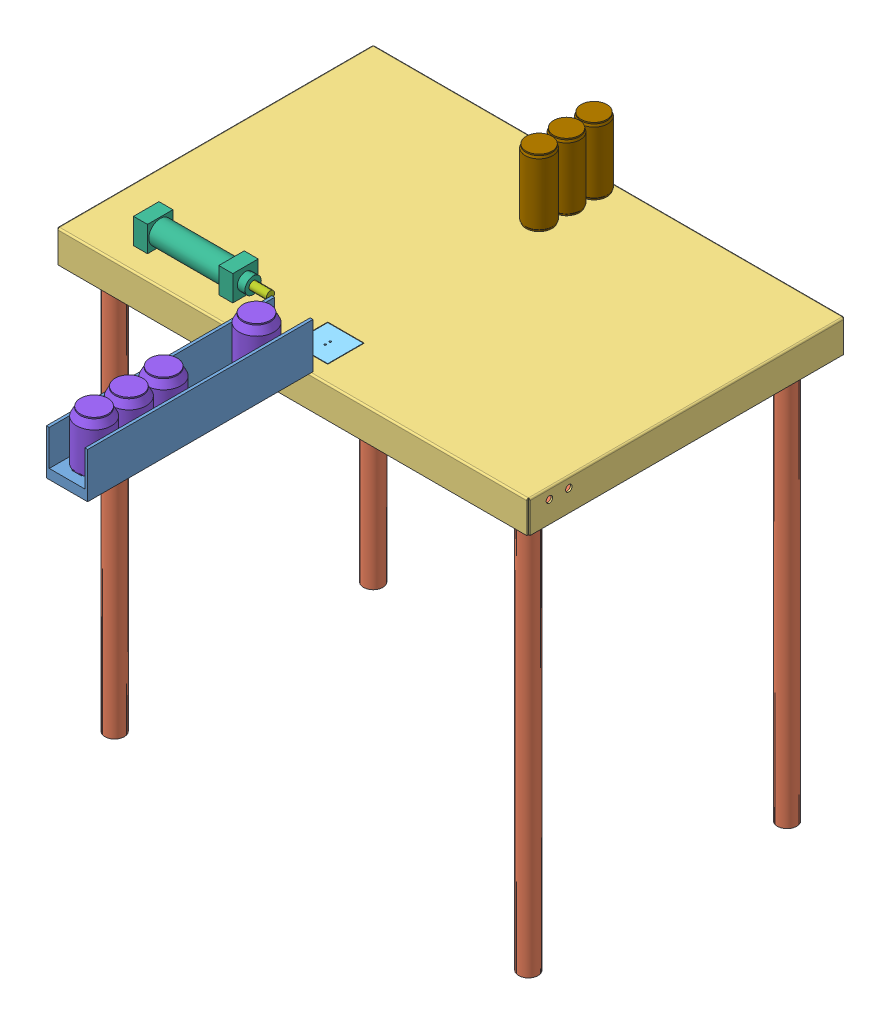
SolidWorks assembly Full_Assembly_v8, configuration Default. Lengths in mm.
Overall size (927.1 1032.54 1072.2).
19 component instances, 12 part files, 63 mates.
Components (placement in the parent):
- Goose Output-1: Goose Output [Default] at (293.9688 417.0931 1038.3317) size (80.96 88.9 442.73)
- M37 Metal Table-1: M37 Metal Table [Default] at (-122.75 348.1681 1031.9817) size (914.4 863.6 609.6)
- Table Topper-1: Table Topper [Default] at (-125.925 348.1681 1035.1567) size (927.1 62.58 622.3)
- Load Cell Assembly-1: Load Cell Assembly [Default] at (309.0555 355.827 890.1864) size (69.85 23.2 103.99)
  - Load Cell and Brace-1: Load Cell and Brace [Default] at (-9.1055 31.7162 92.7424) size (69 14.2 83)
  - scalePlate_v2_234-1: scalePlate_v2_234 [Default] at (-9.5305 54.9162 113.7283) x (0 0 -1) z (-1 0 0) size (69.85 9 69.85)
- Cylinder-1: Cylinder [Default] at (-22.0508 460.7431 943.9897) x (0 0 1) z (1 0 0) size (50 50 210)
- Rod-1: Rod [Default] at (221.9492 435.7431 968.9897) x (0 0.637822 -0.770184) z (0 0.770184 0.637822) size (16 134 16)
- can355mL-1: can355mL [Default] at (334.45 410.7431 1291.3582) x (0 0 -1) z (1 0 0) size (68.26 122.24 68.26)
- can355mL-2: can355mL [Default] at (334.45 410.7431 1427.8832) x (0 0 -1) z (1 0 0) size (68.26 122.24 68.26)
- can355mL-3: can355mL [Default] at (334.45 410.7431 1359.6207) x (0 0 -1) z (1 0 0) size (68.26 122.24 68.26)
- can250mL-1: can250mL [Default] at (334.45 410.7431 553.8493) x (-0.934308 0 -0.356465) z (0.356465 0 -0.934308) size (53.98 131.76 53.98)
- can250mL-2: can250mL [Default] at (334.45 410.7431 499.8743) x (0.439436 0 -0.898274) z (0.898274 0 0.439436) size (53.98 131.76 53.98)
- can250mL-3: can250mL [Default] at (334.45 410.7431 445.8993) x (0.515444 0 0.856923) z (-0.856923 0 0.515444) size (53.98 131.76 53.98)
- can355mL-7: can355mL [Default] at (334.45 410.7431 1108.8451) x (0 0 -1) z (1 0 0) size (68.26 122.24 68.26)
- AmpCase_Assembly_v1-1: AmpCase_Assembly_v1 [Default] at (378.0256 448.8639 898.6464) x (0 0 -1) z (-1 0 0) size (83 33 59)
  - AmpCase_LID_83x59x33_v1-1: AmpCase_LID_83x59x33_v1 [Default] at (42.2994 74.2958 -6.3457) x (1 0 0) z (0 0 -1) size (83 7 59)
  - AmpCase83x59x33_v1-1: AmpCase83x59x33_v1 [Default] at (42.2994 41.2958 52.6543) size (83 26 59)
- Solenoid_v1-1: Solenoid_v1 [Default] at (452.5858 385.5681 857.7853) size (118 22 83)
Mates (geometry in assembly coordinates):
- Width1: width aligned: plane of M37 Metal Table-1 through (791.65 373.5681 1031.9817) normal (1 0 0); plane of M37 Metal Table-1 through (-122.75 373.5681 1031.9817) normal (-1 0 0); plane of Table Topper-1 through (798 407.5681 1035.1567) normal (1 0 0); plane of Table Topper-1 through (-129.1 407.5681 1035.1567) normal (-1 0 0)
- Width2: width aligned: plane of M37 Metal Table-1 through (-122.75 373.5681 1031.9817) normal (0 0 1); plane of M37 Metal Table-1 through (-122.75 373.5681 422.3817) normal (0 0 -1); plane of Table Topper-1 through (-125.925 407.5681 1038.3317) normal (0 0 1); plane of Table Topper-1 through (-125.925 407.5681 416.0317) normal (0 0 -1)
- Distance1: distance = 863.6 mm aligned: plane of M37 Metal Table-1 through (-122.75 -446.5069 1031.9817) normal (0 -1 0); plane of Goose Output-1 through (374.9313 417.0931 1481.0664) normal (0 -1 0)
- LimitDistance1: limit distance = 423.0687 mm aligned: plane of Goose Output-1 through (374.9313 505.9931 1481.0664) normal (1 0 0); plane of Table Topper-1 through (798 407.5681 1035.1567) normal (1 0 0)
- LimitDistance2: limit distance = 423.0687 mm aligned: plane of Table Topper-1 through (-129.1 407.5681 1035.1567) normal (-1 0 0); plane of Goose Output-1 through (293.9688 417.0931 1481.0664) normal (-1 0 0)
- Parallel1: parallel aligned: plane of Goose Output-1 through (299.525 436.1431 1481.0664) normal (0 1 0); plane of Table Topper-1 through (-125.925 410.7431 1035.1567) normal (0 1 0)
- Coincident7: coincident aligned: plane of Table Topper-1 through (-125.925 410.7431 1035.1567) normal (0 1 0); plane of Load Cell Assembly-1/scalePlate_v2_234-1 through (299.525 410.7431 1003.9147) normal (0 1 0)
- Concentric1: concentric anti-aligned: cylinder of Cylinder-1 through (187.9492 435.7431 968.9897) axis (-1 0 0) radius 16; cylinder of Rod-1 through (87.9492 435.7431 968.9897) axis (1 0 0) radius 8
- LimitDistance3: limit distance = 34 mm aligned: plane of Rod-1 through (221.9492 435.7431 968.9897) normal (1 0 0); plane of Cylinder-1 through (187.9492 435.7431 968.9897) normal (1 0 0)
- Parallel2: parallel anti-aligned: plane of Table Topper-1 through (-125.925 407.5681 1038.3317) normal (0 0 1); plane of Cylinder-1 through (172.9492 460.7431 943.9897) normal (0 0 -1)
- Coincident9: coincident anti-aligned: plane of Table Topper-1 through (-125.925 410.7431 1035.1567) normal (0 1 0); plane of Cylinder-1 through (5.4492 410.7431 943.9897) normal (0 -1 0)
- Width3: width anti-aligned: plane of Goose Output-1 through (374.9313 505.9931 1481.0664) normal (1 0 0); plane of Goose Output-1 through (293.9688 417.0931 1481.0664) normal (-1 0 0); plane of Load Cell Assembly-1/scalePlate_v2_234-1 through (299.525 406.7431 1003.9147) normal (-1 0 0); plane of Load Cell Assembly-1/scalePlate_v2_234-1 through (369.375 406.7431 1003.9147) normal (1 0 0)
- Width4: width anti-aligned: plane of Cylinder-1 through (172.9492 460.7431 943.9897) normal (0 0 -1); plane of Cylinder-1 through (172.9492 460.7431 993.9897) normal (0 0 1); plane of Load Cell Assembly-1/scalePlate_v2_234-1 through (299.525 406.7431 1003.9147) normal (0 0 1); plane of Load Cell Assembly-1/scalePlate_v2_234-1 through (299.525 406.7431 934.0647) normal (0 0 -1)
- Width5: width anti-aligned: plane of Table Topper-1 through (798 407.5681 1035.1567) normal (1 0 0); plane of Table Topper-1 through (-129.1 407.5681 1035.1567) normal (-1 0 0); plane of Load Cell Assembly-1/scalePlate_v2_234-1 through (299.525 406.7431 1003.9147) normal (-1 0 0); plane of Load Cell Assembly-1/scalePlate_v2_234-1 through (369.375 406.7431 1003.9147) normal (1 0 0)
- Coincident11: coincident anti-aligned: plane of Table Topper-1 through (-125.925 410.7431 1035.1567) normal (0 1 0); plane of can250mL-1 through (310.7186 410.7431 544.7951) normal (0 -1 0)
- Coincident18: coincident anti-aligned: plane of Table Topper-1 through (-125.925 410.7431 1035.1567) normal (0 1 0); plane of can355mL-2 through (334.45 410.7431 1400.8957) normal (0 -1 0)
- Coincident19: coincident anti-aligned: plane of Table Topper-1 through (-125.925 410.7431 1035.1567) normal (0 1 0); plane of can355mL-3 through (334.45 410.7431 1332.6332) normal (0 -1 0)
- Tangent5: tangent anti-aligned: cylinder of can355mL-2 through (334.45 410.7431 1427.8832) axis (0 -1 0) radius 34.1313; cylinder of can355mL-3 through (334.45 410.7431 1359.6207) axis (0 -1 0) radius 34.1313
- Width6: width: plane of Goose Output-1 through (299.525 505.9931 1481.0664) normal (1 0 0); plane of Goose Output-1 through (369.375 436.1431 1481.0664) normal (-1 0 0); cylinder of can250mL-1 through (334.45 410.7431 553.8493) axis (0 -1 0) radius 26.9875
- Width8: width: plane of Goose Output-1 through (369.375 436.1431 1481.0664) normal (-1 0 0); plane of Goose Output-1 through (299.525 505.9931 1481.0664) normal (1 0 0); cylinder of can355mL-2 through (334.45 410.7431 1427.8832) axis (0 -1 0) radius 34.1313
- Width10: width: plane of Goose Output-1 through (299.525 505.9931 1481.0664) normal (1 0 0); plane of Goose Output-1 through (369.375 436.1431 1481.0664) normal (-1 0 0); cylinder of can355mL-3 through (334.45 410.7431 1359.6207) axis (0 -1 0) radius 34.1313
- Coincident20: coincident anti-aligned: plane of Table Topper-1 through (-125.925 410.7431 1035.1567) normal (0 1 0); plane of can250mL-2 through (345.6117 410.7431 477.0581) normal (0 -1 0)
- Coincident21: coincident anti-aligned: plane of Table Topper-1 through (-125.925 410.7431 1035.1567) normal (0 1 0); plane of can250mL-3 through (347.5423 410.7431 467.6651) normal (0 -1 0)
- Tangent6: tangent anti-aligned: cylinder of can250mL-1 through (334.45 410.7431 553.8493) axis (0 -1 0) radius 26.9875; cylinder of can250mL-2 through (334.45 410.7431 499.8743) axis (0 -1 0) radius 26.9875
- Tangent7: tangent anti-aligned: cylinder of can250mL-2 through (334.45 410.7431 499.8743) axis (0 -1 0) radius 26.9875; cylinder of can250mL-3 through (334.45 410.7431 445.8993) axis (0 -1 0) radius 26.9875
- Width11: width: plane of Goose Output-1 through (299.525 505.9931 1481.0664) normal (1 0 0); plane of Goose Output-1 through (369.375 436.1431 1481.0664) normal (-1 0 0); cylinder of can250mL-2 through (334.45 410.7431 499.8743) axis (0 -1 0) radius 26.9875
- Width12: width: plane of Goose Output-1 through (299.525 505.9931 1481.0664) normal (1 0 0); plane of Goose Output-1 through (369.375 436.1431 1481.0664) normal (-1 0 0); cylinder of can250mL-3 through (334.45 410.7431 445.8993) axis (0 -1 0) radius 26.9875
- Coincident22: coincident anti-aligned: plane of Goose Output-1 through (293.9688 417.0931 1038.3317) normal (0 0 -1); plane of Table Topper-1 through (-125.925 407.5681 1038.3317) normal (0 0 1)
- Width14: width aligned: plane of Table Topper-1 through (370.391 348.1681 1004.9307) normal (-1 0 0); plane of Load Cell Assembly-1/scalePlate_v2_234-1 through (298.509 348.1681 1004.9307) normal (1 0 0); plane of Table Topper-1 through (299.525 406.7431 1003.9147) normal (-1 0 0); plane of Load Cell Assembly-1/scalePlate_v2_234-1 through (369.375 406.7431 1003.9147) normal (1 0 0)
- Width15: width anti-aligned: plane of Table Topper-1 through (298.509 348.1681 1004.9307) normal (0 0 -1); plane of Load Cell Assembly-1/scalePlate_v2_234-1 through (298.509 348.1681 933.0487) normal (0 0 1); plane of Table Topper-1 through (299.525 406.7431 1003.9147) normal (0 0 1); plane of Load Cell Assembly-1/scalePlate_v2_234-1 through (299.525 406.7431 934.0647) normal (0 0 -1)
- Width17: width: plane of Goose Output-1 through (369.375 436.1431 1481.0664) normal (-1 0 0); plane of can355mL-4 through (299.525 505.9931 1481.0664) normal (1 0 0); cylinder of Goose Output-1 through (334.45 436.1431 1259.8293) axis (0 -1 0) radius 34.1313
- Coincident31: coincident anti-aligned: plane of Table Topper-1 through (-125.925 410.7431 1035.1567) normal (0 1 0); plane of can355mL-7 through (334.45 410.7431 1081.8576) normal (0 -1 0)
- Width19: width: plane of Goose Output-1 through (369.375 436.1431 1481.0664) normal (-1 0 0); plane of can355mL-7 through (299.525 505.9931 1481.0664) normal (1 0 0); cylinder of Goose Output-1 through (334.45 410.7431 1108.8451) axis (0 -1 0) radius 34.1313
- Coincident33: coincident anti-aligned: plane of Table Topper-1 through (-125.925 410.7431 1035.1567) normal (0 1 0); plane of can355mL-1 through (334.45 410.7431 1264.3707) normal (0 -1 0)
- Tangent13: tangent anti-aligned: cylinder of can355mL-1 through (334.45 410.7431 1291.3582) axis (0 -1 0) radius 34.1313; cylinder of can355mL-3 through (334.45 410.7431 1359.6207) axis (0 -1 0) radius 34.1313
- Width20: width: plane of Goose Output-1 through (299.525 505.9931 1481.0664) normal (1 0 0); plane of can355mL-1 through (369.375 436.1431 1481.0664) normal (-1 0 0); cylinder of Goose Output-1 through (334.45 410.7431 1291.3582) axis (0 -1 0) radius 34.1313
- Parallel4: parallel aligned: plane of M37 Metal Table-1 through (-122.75 373.5681 1031.9817) normal (0 0 1); plane of can355mL-7 through (334.45 410.7431 1142.9764) normal (0 0 1)
- Parallel5: parallel aligned: plane of M37 Metal Table-1 through (-122.75 373.5681 1031.9817) normal (0 0 1); plane of can355mL-2 through (334.45 410.7431 1462.0144) normal (0 0 1)
- Parallel6: parallel aligned: plane of M37 Metal Table-1 through (-122.75 373.5681 1031.9817) normal (0 0 1); plane of can355mL-3 through (334.45 410.7431 1393.7519) normal (0 0 1)
- Parallel7: parallel aligned: plane of M37 Metal Table-1 through (-122.75 373.5681 1031.9817) normal (0 0 1); plane of can355mL-1 through (334.45 410.7431 1325.4894) normal (0 0 1)
- LimitDistance14: limit distance = 182.5131 mm aligned: plane of can355mL-7 through (334.45 410.7431 1142.9764) normal (0 0 1); plane of can355mL-1 through (334.45 410.7431 1325.4894) normal (0 0 1)
- Tangent14: tangent anti-aligned: cylinder of can355mL-9 through (334.45 412.9931 1319.9352) axis (0 -1 0) radius 34.1313; cylinder of can355mL-10 through (334.45 412.9931 1388.1977) axis (0 -1 0) radius 34.1313
- Tangent15: tangent anti-aligned: cylinder of can355mL-8 through (334.45 412.9931 1456.4602) axis (0 -1 0) radius 34.1313; cylinder of can355mL-10 through (334.45 412.9931 1388.1977) axis (0 -1 0) radius 34.1313
- Coincident38: coincident anti-aligned: plane of Table Topper-1 through (-125.925 410.7431 1035.1567) normal (0 1 0); plane of can355mL-8 through (334.45 412.9931 1429.4727) normal (0 -1 0)
- Coincident39: coincident aligned: plane of can355mL-9 through (334.45 412.9931 1292.9477) normal (0 -1 0); plane of can355mL-10 through (334.45 412.9931 1361.2102) normal (0 -1 0)
- Coincident40: coincident anti-aligned: plane of Table Topper-1 through (-125.925 410.7431 1035.1567) normal (0 1 0); plane of can355mL-10 through (334.45 412.9931 1361.2102) normal (0 -1 0)
- Width21: width: plane of Goose Output-1 through (299.525 505.9931 1481.0664) normal (1 0 0); plane of Goose Output-1 through (369.375 436.1431 1481.0664) normal (-1 0 0); cylinder of can355mL-8 through (334.45 412.9931 1456.4602) axis (0 -1 0) radius 34.1313
- Width22: width: plane of Goose Output-1 through (374.9313 505.9931 1481.0664) normal (1 0 0); plane of Goose Output-1 through (293.9688 417.0931 1481.0664) normal (-1 0 0); cylinder of can355mL-10 through (334.45 412.9931 1388.1977) axis (0 -1 0) radius 34.1313
- Width23: width: plane of Goose Output-1 through (374.9313 505.9931 1481.0664) normal (1 0 0); plane of Goose Output-1 through (293.9688 417.0931 1481.0664) normal (-1 0 0); cylinder of can355mL-9 through (334.45 412.9931 1319.9352) axis (0 -1 0) radius 34.1313
- LimitDistance15: limit distance = 98.6078 mm aligned: plane of can355mL-9 through (334.45 412.9931 1354.0664) normal (0 0 1); plane of can355mL-2 through (334.45 410.7431 1462.0144) normal (0 0 1)
- Parallel8: parallel aligned: plane of M37 Metal Table-1 through (-122.75 373.5681 1031.9817) normal (0 0 1); plane of can355mL-8 through (334.45 412.9931 1490.5914) normal (0 0 1)
- Parallel10: parallel aligned: plane of M37 Metal Table-1 through (-122.75 373.5681 1031.9817) normal (0 0 1); plane of can355mL-10 through (334.45 412.9931 1422.3289) normal (0 0 1)
- LimitDistance16: limit distance = 0 mm aligned: plane of can355mL-8 through (334.45 412.9931 1490.5914) normal (0 0 1); plane of Goose Output-1 through (293.9688 417.0931 1481.0664) normal (0 0 1)
- Parallel12: parallel aligned: plane of M37 Metal Table-1 through (-122.75 373.5681 1031.9817) normal (0 0 1); plane of can355mL-11 through (334.45 412.9931 1012.7539) normal (0 0 1)
- LimitDistance18: limit distance = 68.2625 mm aligned: plane of can355mL-11 through (334.45 412.9931 1012.7539) normal (0 0 1); plane of can355mL-7 through (334.45 410.7431 1142.9764) normal (0 0 1)
- PathMate3: path: point of can355mL-11
- Parallel13: parallel anti-aligned: plane of Table Topper-1 through (-125.925 410.7431 1035.1567) normal (0 1 0); plane of can355mL-11 through (334.45 412.9931 951.6352) normal (0 -1 0)
- Parallel14: parallel aligned: plane of M37 Metal Table-1 through (-122.75 373.5681 1031.9817) normal (0 0 1); plane of can355mL-11 through (334.45 412.9931 1012.7539) normal (0 0 1)
- Coincident41: coincident aligned: plane of M37 Metal Table-1 through (-122.75 348.1681 1031.9817) normal (0 -1 0); plane of Table Topper-1 through (-125.925 348.1681 1035.1567) normal (0 -1 0)
- Coincident42: coincident anti-aligned: plane of Table Topper-1 through (-125.925 407.5681 1035.1567) normal (0 -1 0); plane of AmpCase_Assembly_v1-1/AmpCase83x59x33_v1-1 through (325.3712 407.5681 856.347) normal (0 1 0)
- Parallel15: parallel aligned: plane of M37 Metal Table-1 through (-122.75 373.5681 1031.9817) normal (0 0 1); plane of AmpCase_Assembly_v1-1/AmpCase83x59x33_v1-1 through (325.3712 404.5681 856.347) normal (0 0 1)
- Parallel16: parallel aligned: plane of M37 Metal Table-1 through (-122.75 373.5681 1031.9817) normal (0 0 1); plane of Solenoid_v1-1 through (452.5858 407.5681 857.7853) normal (0 0 1)
- Coincident45: coincident aligned: plane of AmpCase_Assembly_v1-1/AmpCase83x59x33_v1-1 through (325.3712 407.5681 856.347) normal (0 1 0); plane of Solenoid_v1-1 through (452.5858 407.5681 857.7853) normal (0 1 0)
